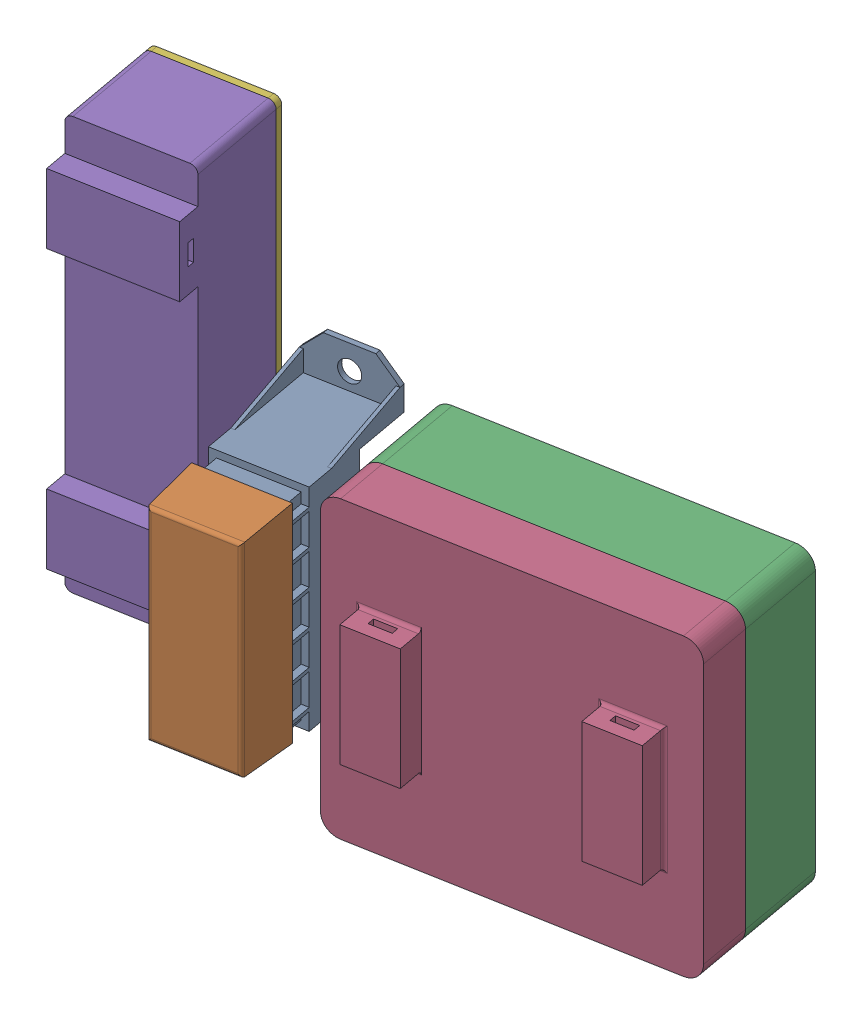
SolidWorks assembly PUTM-G-BX-Assembly, configuration Domyślna. Lengths in mm.
Overall size (171.13 145.08 78.74).
5 component instances, 4 part files, 0 mates.
Components (placement in the parent):
- PUTM-G-EB-FuseBox_Front-1: PUTM-G-EB-FuseBox_Front [Domyślna] at (358.5236 -28.1079 493.3816) x (0 1 0) z (0.178486 0 0.983943) size (85 25 57)
- PUTM-G-TM-APPS_KartaPomiarowa-1: PUTM-G-TM-APPS_KartaPomiarowa [Domyślna] at (471.8903 -87.39 449.4417) x (0 1 0) z (0.983943 0 -0.178486) size (85 47.5 95)
- PUTM-G-BX-BSPD-1: PUTM-G-BX-BSPD [Domyślna] at (330.8255 -1.8057 505.5202) x (0 1 0) z (-0.983943 0 0.178486) size (119 36.5 33)
  - PUTM-G-BX-BSPD_pojemnik-1: PUTM-G-BX-BSPD_pojemnik [Domyślna] at origin size (119 34.5 33)
  - PUTM-G-BX-BSPD_Cover-1: PUTM-G-BX-BSPD_Cover [Domyślna] at (0 28 0) x (1 0 0) z (0 1 0) size (119 33 3)
